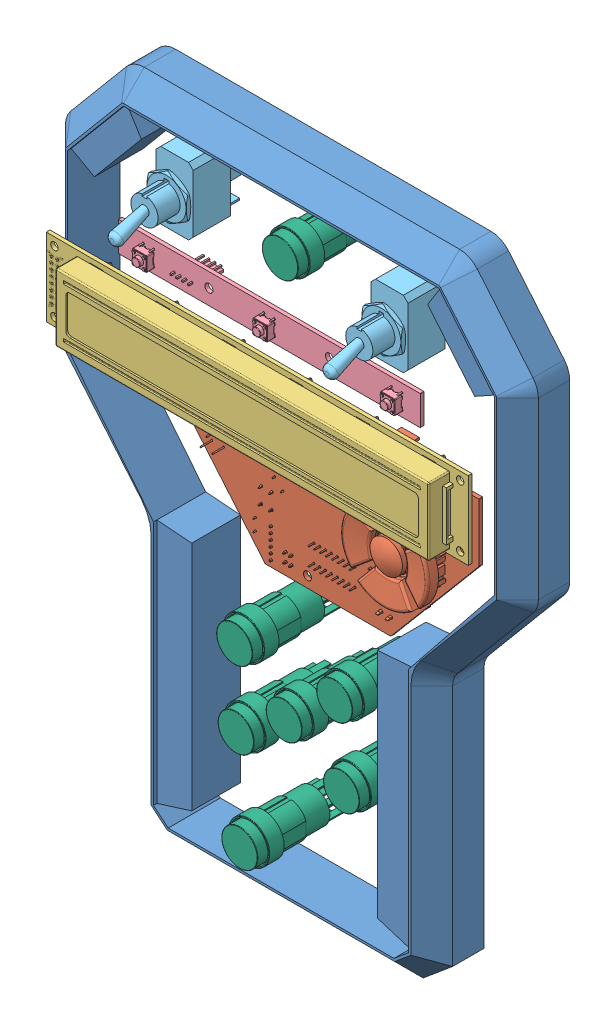
SolidWorks assembly Montagem005, configuration Valor predeterminado. Lengths in mm.
Overall size (204 280 70.6).
13 component instances, 6 part files, 1 mates.
Components (placement in the parent):
- 5 - TEC02 - Moldura-1: 5 - TEC02 - Moldura [Valor predeterminado] at (-77.5056 -133.06 -11.25) size (204 280 22.5)
- PCB_IHM-1: PCB_IHM [Valor predeterminado] at (-104.1662 -11.7809 -8.6761) size (130.25 70.25 27.35)
- LCD Display 4002-1: LCD Display 4002 [Valor predeterminado] at (-77.0232 78.6626 17.4273) size (182 33.5 13.65)
- PCB_IHM_Teclas_Superiores-1: PCB_IHM_Teclas_Superiores [Valor predeterminado] at (-143.4716 96.4826 15.34) size (130.25 12.75 19.2)
- BCV3 112 103 - Controle chave geral-1: BCV3 112 103 - Controle chave geral [Default] at (-124.6429 125.6495 2) size (17 29 51.5)
- BCV3 112 103 - Controle chave geral-2: BCV3 112 103 - Controle chave geral [Default] at (-29.5024 124.8727 4.4985) size (17 29 51.5)
- BCV3 112 102 - Controle botão-1: BCV3 112 102 - Controle botão [Valor predeterminado] at (-77.9388 125.3833 0.85) x (1 0 0) z (0 -1 0) size (17.7 39.7 17.7)
- BCV3 112 102 - Controle botão-2: BCV3 112 102 - Controle botão [Valor predeterminado] at (-76.3403 -46.4219 0.7739) x (1 0 0) z (0 -1 0) size (17.7 39.7 17.7)
- BCV3 112 102 - Controle botão-3: BCV3 112 102 - Controle botão [Valor predeterminado] at (-75.5634 -83.7106 20.7) x (1 0 0) z (0 -1 0) size (17.7 39.7 17.7)
- BCV3 112 102 - Controle botão-4: BCV3 112 102 - Controle botão [Valor predeterminado] at (-54.2002 -63.1241 -1.8) x (1 0 0) z (0 -1 0) size (17.7 39.7 17.7)
- BCV3 112 102 - Controle botão-5: BCV3 112 102 - Controle botão [Valor predeterminado] at (-99.6457 -63.901 -1.8) x (1 0 0) z (0 -1 0) size (17.7 39.7 17.7)
- BCV3 112 102 - Controle botão-6: BCV3 112 102 - Controle botão [Valor predeterminado] at (-54.5886 -28.166 0.7739) x (1 0 0) z (0 -1 0) size (17.7 39.7 17.7)
- BCV3 112 102 - Controle botão-7: BCV3 112 102 - Controle botão [Valor predeterminado] at (-97.7036 -28.5545 0.7739) x (1 0 0) z (0 -1 0) size (17.7 39.7 17.7)
Mates (geometry in assembly coordinates):
- Coincidente2: coincident aligned: plane of 5 - TEC02 - Moldura-1 through (-77.5056 -133.06 11.25) normal (0 0 1); plane of BCV3 112 102 - Controle botão-1 through (-77.9388 125.3833 11.25) normal (0 0 1)
